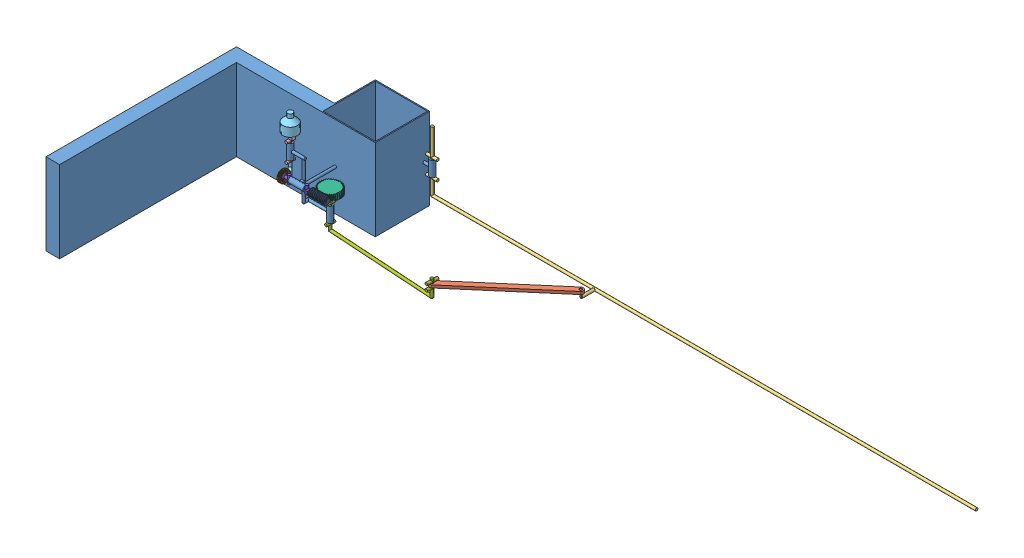
SolidWorks assembly Sc cote 730 SW, configuration Défaut. Lengths in mm.
Overall size (2590 357 850).
13 component instances, 10 part files, 12 mates.
Components (placement in the parent):
- Bati-1: Bati [Défaut] at (235 235 -534.5) x (0 0 1) z (0 1 0) size (850 600 300)
- Bielle-2: Bielle [Défaut] at (764.1881 82.5 -526.0272) x (0.759332 0 -0.650703) z (0 -1 0) size (408 20 10)
- vantail-2: vantail [Défaut] at (462 57.5 -830) x (1 0 0) z (0 1 0) size (2020 61.5 225)
- arbre moteur-2: arbre moteur [Défaut] at (235 292.5 -534.5) x (0 -1 0) z (0 0 1) size (214.5 74.88 74.88)
  - arbre moteur-1: arbre moteur [Défaut] at origin size (150 10 30)
  - vis moteur-1: vis moteur [Défaut] at (122.5 0 0) x (0 -0.73755 -0.675292) z (-1 0 0) size (53 53 214.5)
- arbre sortie-1: arbre sortie [Défaut] at (365 165 -551.5) x (-0.063682 0 0.99797) z (0 -1 0) size (74.27 442.1 142.5)
  - roue arbre sortie-1: roue arbre sortie [Défaut] at origin size (74.27 74.24 20)
  - arbre sortie + bras-1: arbre sortie + bras [Défaut] at (0 0 127.5) x (1 0 0) z (0 1 0) size (40 122.5 410)
- arbtre intermediaire-1: arbtre intermediaire [Défaut] at (227.5 165 -510.9) x (1 0 0) z (0 1 0) size (168.32 41.72 41.74)
  - arbre intermediaire-1: arbre intermediaire [Défaut] at origin size (153 30 30)
  - EngrHelicD3PA5418-1: EngrHelicD3PA5418 [Défaut] at (7.5 0 0) x (0 0 -1) z (1 0 0) size (41.74 41.72 11)
  - arbre-1: arbre [Défaut] at (137.8171 0 0) x (0 0 1) z (-1 0 0) size (27.87 26.95 65)
Mates (geometry in assembly coordinates):
- Coaxiale1: concentric anti-aligned: cylinder of Bati-1; cylinder of arbre moteur-2/vis moteur-1
- Tangent1: tangent anti-aligned: plane of Bati-1 through (235 262.5 -534.5) normal (0 1 0); cylinder of arbre moteur-2/arbre moteur-1
- Coaxiale2: concentric aligned: cylinder of Bati-1; cylinder of arbtre intermediaire-1/arbre intermediaire-1
- Tangent3: tangent anti-aligned: plane of Bati-1 through (315 165 -510.9) normal (1 0 0); cylinder of arbtre intermediaire-1/arbre intermediaire-1
- Coaxiale3: concentric anti-aligned: cylinder of Bati-1; cylinder of arbre sortie-1/arbre sortie + bras-1
- Tangent4: tangent anti-aligned: plane of Bati-1 through (365 120 -551.5) normal (0 1 0); cylinder of arbre sortie-1/arbre sortie + bras-1
- Coaxiale4: concentric aligned: cylinder of Bati-1; cylinder of vantail-2
- Tangent5: tangent anti-aligned: plane of Bati-1 through (462 175 -830) normal (0 1 0); cylinder of vantail-2
- Coaxiale5: concentric anti-aligned: cylinder of Bielle-2; cylinder of arbre sortie-1/arbre sortie + bras-1
- Tangent6: tangent anti-aligned: plane of Bielle-2 through (670.1281 82.5 -445.4234) normal (0 1 0); cylinder of arbre sortie-1/arbre sortie + bras-1
- Tangent7: tangent aligned: cylinder of Bielle-2; sphere of vantail-2
- Parallèle1: parallel aligned: plane of Bati-1 through (432 0 -850) normal (1 0 0); plane of vantail-2 through (482 115 -830) normal (1 0 0)
